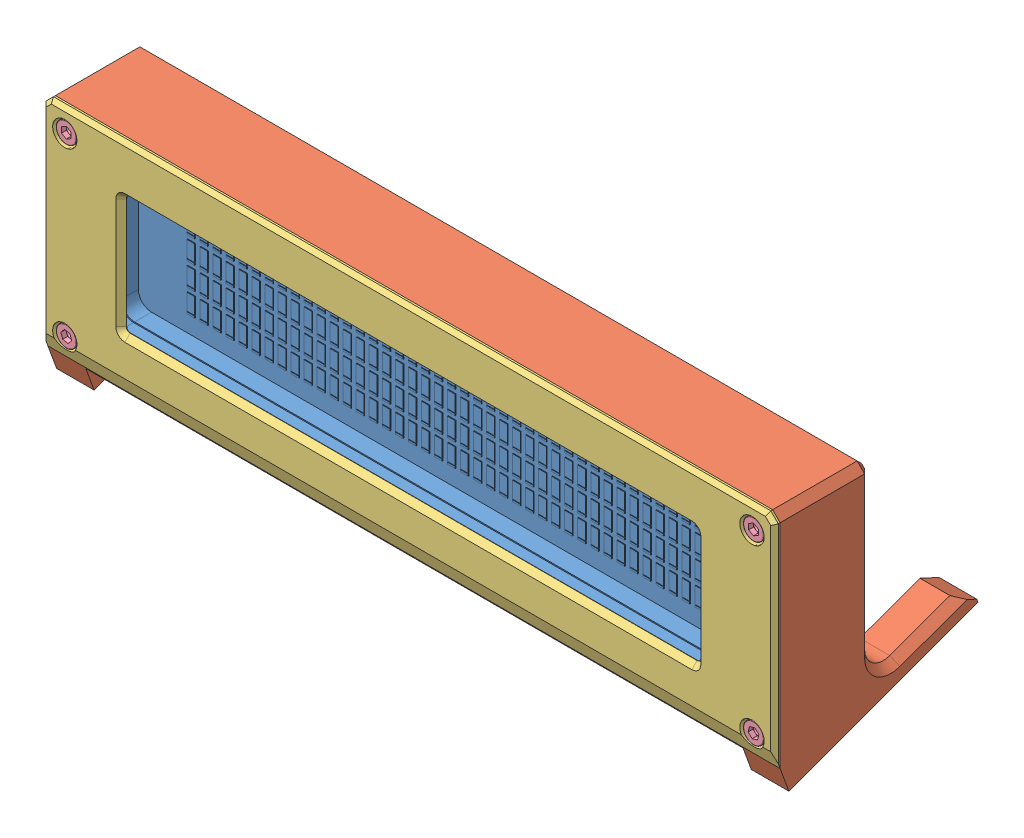
SolidWorks assembly Ensamblaje3, configuration Default. Lengths in mm.
Overall size (195 65.07 54.19).
244 component instances, 157 part files, 27 mates.
Components (placement in the parent):
- cu40045-uw1j-1: cu40045-uw1j [Default] at (-133.5972 17.1888 55.2046) size (190 54 18.77)
- 61301821121_Download_IGS_61301821121_rev1-1: 61301821121_Download_IGS_61301821121_rev1 [Default] at (-223.5572 15.9188 58.0746) x (0 -1 0) z (1 0 0) size (22.86 11.54 5.08)
  - DEFAULT-1: DEFAULT [Predeterminado] at origin size (22.86 11.54 5.08)
    - DEFAULT-1: DEFAULT [Predeterminado] at (-10.16 1.5 0) x (1 0 0) z (0 -1 0) size (0.64 0.64 11.54)
    - DEFAULT-2: DEFAULT [Predeterminado] at (-10.16 1.5 -2.54) x (1 0 0) z (0 -1 0) size (0.64 0.64 11.54)
    - DEFAULT-3: DEFAULT [Predeterminado] at (-7.62 1.5 0) x (1 0 0) z (0 -1 0) size (0.64 0.64 11.54)
    - DEFAULT-4: DEFAULT [Predeterminado] at (-7.62 1.5 -2.54) x (1 0 0) z (0 -1 0) size (0.64 0.64 11.54)
    - DEFAULT-5: DEFAULT [Predeterminado] at (-5.08 1.5 0) x (1 0 0) z (0 -1 0) size (0.64 0.64 11.54)
    - DEFAULT-6: DEFAULT [Predeterminado] at (-5.08 1.5 -2.54) x (1 0 0) z (0 -1 0) size (0.64 0.64 11.54)
    - DEFAULT-7: DEFAULT [Predeterminado] at (-2.54 1.5 0) x (1 0 0) z (0 -1 0) size (0.64 0.64 11.54)
    - DEFAULT-8: DEFAULT [Predeterminado] at (-2.54 1.5 -2.54) x (1 0 0) z (0 -1 0) size (0.64 0.64 11.54)
    - DEFAULT-9: DEFAULT [Predeterminado] at (0 1.5 0) x (1 0 0) z (0 -1 0) size (0.64 0.64 11.54)
    - DEFAULT-10: DEFAULT [Predeterminado] at (0 1.5 -2.54) x (1 0 0) z (0 -1 0) size (0.64 0.64 11.54)
    - DEFAULT-11: DEFAULT [Predeterminado] at (2.54 1.5 0) x (1 0 0) z (0 -1 0) size (0.64 0.64 11.54)
    - DEFAULT-12: DEFAULT [Predeterminado] at (2.54 1.5 -2.54) x (1 0 0) z (0 -1 0) size (0.64 0.64 11.54)
    - DEFAULT-13: DEFAULT [Predeterminado] at (5.08 1.5 0) x (1 0 0) z (0 -1 0) size (0.64 0.64 11.54)
    - DEFAULT-14: DEFAULT [Predeterminado] at (5.08 1.5 -2.54) x (1 0 0) z (0 -1 0) size (0.64 0.64 11.54)
    - DEFAULT-15: DEFAULT [Predeterminado] at (7.62 1.5 0) x (1 0 0) z (0 -1 0) size (0.64 0.64 11.54)
    - DEFAULT-16: DEFAULT [Predeterminado] at (7.62 1.5 -2.54) x (1 0 0) z (0 -1 0) size (0.64 0.64 11.54)
    - DEFAULT-17: DEFAULT [Predeterminado] at (10.16 1.5 0) x (1 0 0) z (0 -1 0) size (0.64 0.64 11.54)
    - DEFAULT-18: DEFAULT [Predeterminado] at (10.16 1.5 -2.54) x (1 0 0) z (0 -1 0) size (0.64 0.64 11.54)
    - DEFAULT-1-1: DEFAULT-1 [Predeterminado] at origin size (22.86 2.54 5.08)
- pic backpack-1: pic backpack [Default] at (-239.4322 -8.7192 50.6016) x (-1 0 0) z (0 0 -1) size (33.69 32.08 21.86)
  - Layer_1-1: Layer_1 [Predeterminado] at origin size (33.66 25.02 1.61)
  - J1-1: J1 [Predeterminado] at (-14.605 24.638 -0.803) x (0 -1 0) z (0 0 -1) size (22.86 7.4 5.5)
    - Open CASCADE STEP translator 6.8 1.2.1-1: Open CASCADE STEP translator 6.8 1.2.1 [Predeterminado] at origin size (22.86 7.4 5.5)
      - Body_1-1: Body_1 [Predeterminado] at origin size (22.86 7.4 5.5)
        - =_[0_1_1_2]-1: =_[0_1_1_2] [Predeterminado] at (0 0 0.1) size (22.86 5.08 3.7)
        - =_[0_1_1_3]-1: =_[0_1_1_3] [Predeterminado] at origin size (21.14 7.4 0.1)
          - SOLID-1: SOLID [Predeterminado] at origin size (0.82 1.58 0.1)
          - SOLID_2-1: SOLID_2 [Predeterminado] at origin size (0.82 1.58 0.1)
          - SOLID_3-1: SOLID_3 [Predeterminado] at origin size (0.82 1.58 0.1)
          - SOLID_4-1: SOLID_4 [Predeterminado] at origin size (0.82 1.58 0.1)
          - SOLID_5-1: SOLID_5 [Predeterminado] at origin size (0.82 1.58 0.1)
          - SOLID_6-1: SOLID_6 [Predeterminado] at origin size (0.82 1.58 0.1)
          - SOLID_7-1: SOLID_7 [Predeterminado] at origin size (0.82 1.58 0.1)
          - SOLID_8-1: SOLID_8 [Predeterminado] at origin size (0.82 1.58 0.1)
          - SOLID_9-1: SOLID_9 [Predeterminado] at origin size (0.82 1.58 0.1)
          - SOLID_10-1: SOLID_10 [Predeterminado] at origin size (0.82 1.58 0.1)
          - SOLID_11-1: SOLID_11 [Predeterminado] at origin size (0.82 1.58 0.1)
          - SOLID_12-1: SOLID_12 [Predeterminado] at origin size (0.82 1.58 0.1)
          - SOLID_13-1: SOLID_13 [Predeterminado] at origin size (0.82 1.58 0.1)
          - SOLID_14-1: SOLID_14 [Predeterminado] at origin size (0.82 1.58 0.1)
          - SOLID_15-1: SOLID_15 [Predeterminado] at origin size (0.82 1.58 0.1)
          - SOLID_16-1: SOLID_16 [Predeterminado] at origin size (0.82 1.58 0.1)
          - SOLID_17-1: SOLID_17 [Predeterminado] at origin size (0.82 1.58 0.1)
          - SOLID_18-1: SOLID_18 [Predeterminado] at origin size (0.82 1.58 0.1)
        - =_[0_1_1_4]-1: =_[0_1_1_4] [Predeterminado] at origin size (21.14 3.36 1.8)
          - SOLID_19-1: SOLID_19 [Predeterminado] at origin size (0.82 0.82 1.8)
          - SOLID_20-1: SOLID_20 [Predeterminado] at origin size (0.82 0.82 1.8)
          - SOLID_21-1: SOLID_21 [Predeterminado] at origin size (0.82 0.82 1.8)
          - SOLID_22-1: SOLID_22 [Predeterminado] at origin size (0.82 0.82 1.8)
          - SOLID_23-1: SOLID_23 [Predeterminado] at origin size (0.82 0.82 1.8)
          - SOLID_24-1: SOLID_24 [Predeterminado] at origin size (0.82 0.82 1.8)
          - SOLID_25-1: SOLID_25 [Predeterminado] at origin size (0.82 0.82 1.8)
          - SOLID_26-1: SOLID_26 [Predeterminado] at origin size (0.82 0.82 1.8)
          - SOLID_27-1: SOLID_27 [Predeterminado] at origin size (0.82 0.82 1.8)
          - SOLID_28-1: SOLID_28 [Predeterminado] at origin size (0.82 0.82 1.8)
          - SOLID_29-1: SOLID_29 [Predeterminado] at origin size (0.82 0.82 1.8)
          - SOLID_30-1: SOLID_30 [Predeterminado] at origin size (0.82 0.82 1.8)
          - SOLID_31-1: SOLID_31 [Predeterminado] at origin size (0.82 0.82 1.8)
          - SOLID_32-1: SOLID_32 [Predeterminado] at origin size (0.82 0.82 1.8)
          - SOLID_33-1: SOLID_33 [Predeterminado] at origin size (0.82 0.82 1.8)
          - SOLID_34-1: SOLID_34 [Predeterminado] at origin size (0.82 0.82 1.8)
          - SOLID_35-1: SOLID_35 [Predeterminado] at origin size (0.82 0.82 1.8)
          - SOLID_36-1: SOLID_36 [Predeterminado] at origin size (0.82 0.82 1.8)
          - SOLID_37-1: SOLID_37 [Predeterminado] at origin size (1.6 1.6 1.8)
          - SOLID_38-1: SOLID_38 [Predeterminado] at origin size (1.6 1.6 1.8)
  - U1-1: U1 [Predeterminado] at (-27.559 28.448 0.803) size (9.65 18 2.64)
    - Open CASCADE STEP translator 6.8 1.3.1-1: Open CASCADE STEP translator 6.8 1.3.1 [Predeterminado] at origin size (9.65 18 2.64)
      - Body_1-1: Body_1 [Predeterminado] at origin size (7.3 18 2.38)
      - Pin_1-1: Pin_1 [Predeterminado] at origin size (1.17 0.51 1.58)
      - Pin_2-1: Pin_2 [Predeterminado] at origin size (1.17 0.51 1.58)
      - Pin_3-1: Pin_3 [Predeterminado] at origin size (1.17 0.51 1.58)
      - Pin_4-1: Pin_4 [Predeterminado] at origin size (1.17 0.51 1.58)
      - Pin_5-1: Pin_5 [Predeterminado] at origin size (1.17 0.51 1.58)
      - Pin_6-1: Pin_6 [Predeterminado] at origin size (1.17 0.51 1.58)
      - Pin_7-1: Pin_7 [Predeterminado] at origin size (1.17 0.51 1.58)
      - Pin_8-1: Pin_8 [Predeterminado] at origin size (1.17 0.51 1.58)
      - Pin_9-1: Pin_9 [Predeterminado] at origin size (1.17 0.51 1.58)
      - Pin_10-1: Pin_10 [Predeterminado] at origin size (1.17 0.51 1.58)
      - Pin_11-1: Pin_11 [Predeterminado] at origin size (1.17 0.51 1.58)
      - Pin_12-1: Pin_12 [Predeterminado] at origin size (1.17 0.51 1.58)
      - Pin_13-1: Pin_13 [Predeterminado] at origin size (1.17 0.51 1.58)
      - Pin_14-1: Pin_14 [Predeterminado] at origin size (1.17 0.51 1.58)
      - Pin_15-1: Pin_15 [Predeterminado] at (18.8 -17.78 0) x (-1 0 0) z (0 0 1) size (1.17 0.51 1.58)
      - Pin_16-1: Pin_16 [Predeterminado] at (18.8 -15.24 0) x (-1 0 0) z (0 0 1) size (1.17 0.51 1.58)
      - Pin_17-1: Pin_17 [Predeterminado] at (18.8 -12.7 0) x (-1 0 0) z (0 0 1) size (1.17 0.51 1.58)
      - Pin_18-1: Pin_18 [Predeterminado] at (18.8 -10.16 0) x (-1 0 0) z (0 0 1) size (1.17 0.51 1.58)
      - Pin_19-1: Pin_19 [Predeterminado] at (18.8 -7.62 0) x (-1 0 0) z (0 0 1) size (1.17 0.51 1.58)
      - Pin_20-1: Pin_20 [Predeterminado] at (18.8 -5.08 0) x (-1 0 0) z (0 0 1) size (1.17 0.51 1.58)
      - Pin_21-1: Pin_21 [Predeterminado] at (18.8 -2.54 0) x (-1 0 0) z (0 0 1) size (1.17 0.51 1.58)
      - Pin_22-1: Pin_22 [Predeterminado] at (18.8 0 0) x (-1 0 0) z (0 0 1) size (1.17 0.51 1.58)
      - Pin_23-1: Pin_23 [Predeterminado] at (18.8 2.54 0) x (-1 0 0) z (0 0 1) size (1.17 0.51 1.58)
      - Pin_24-1: Pin_24 [Predeterminado] at (18.8 5.08 0) x (-1 0 0) z (0 0 1) size (1.17 0.51 1.58)
      - Pin_25-1: Pin_25 [Predeterminado] at (18.8 7.62 0) x (-1 0 0) z (0 0 1) size (1.17 0.51 1.58)
      - Pin_26-1: Pin_26 [Predeterminado] at (18.8 10.16 0) x (-1 0 0) z (0 0 1) size (1.17 0.51 1.58)
      - Pin_27-1: Pin_27 [Predeterminado] at (18.8 12.7 0) x (-1 0 0) z (0 0 1) size (1.17 0.51 1.58)
      - Pin_28-1: Pin_28 [Predeterminado] at (18.8 15.24 0) x (-1 0 0) z (0 0 1) size (1.17 0.51 1.58)
  - U2-1: U2 [Predeterminado] at (-20.066 16.383 0.803) x (-1 0 0) z (0 0 1) size (5 3.22 1.3)
    - Open CASCADE STEP translator 6.8 1.4.1-1: Open CASCADE STEP translator 6.8 1.4.1 [Predeterminado] at origin size (5 3.22 1.3)
      - Body_1_2-1: Body_1_2 [Predeterminado] at (0 0 0.25) x (1 0 0) z (0 -1 0) size (5 1.3 3.22)
        - =_[0_1_1_3]-1: =_[0_1_1_3] [Predeterminado] at origin size (1.25 0.05 2)
        - =_[0_1_1_4]-1: =_[0_1_1_4] [Predeterminado] at origin size (1.25 0.05 2)
        - =_[0_1_1_5]-1: =_[0_1_1_5] [Predeterminado] at origin size (5 1.3 3.22)
  - C2-1: C2 [Predeterminado] at (-26.035 17.907 0.803) x (0 -1 0) z (0 0 1) size (2.34 1.04 0.5)
    - Open CASCADE STEP translator 6.8 1.5.1-1: Open CASCADE STEP translator 6.8 1.5.1 [Predeterminado] at origin size (2.34 1.04 0.5)
      - Body_1_2-1: Body_1_2 [Predeterminado] at origin size (2.29 1.04 0.43)
      - Pin_1_2-1: Pin_1_2 [Predeterminado] at (0.3048 0 0) x (-1 0 0) z (0 0 1) size (0.51 1.02 0.5)
      - Pin_2_2-1: Pin_2_2 [Predeterminado] at origin size (0.51 1.02 0.5)
  - C4-1: C4 [Predeterminado] at (-29.591 16.383 0.803) x (0 1 0) z (0 0 1) size (2.34 1.04 0.5)
    - Open CASCADE STEP translator 6.8 1.5.1-1: Open CASCADE STEP translator 6.8 1.5.1 [Predeterminado] at origin size (2.34 1.04 0.5)
      - Body_1_2-1: Body_1_2 [Predeterminado] at origin size (2.29 1.04 0.43)
      - Pin_1_2-1: Pin_1_2 [Predeterminado] at (0.3048 0 0) x (-1 0 0) z (0 0 1) size (0.51 1.02 0.5)
      - Pin_2_2-1: Pin_2_2 [Predeterminado] at origin size (0.51 1.02 0.5)
  - C5-1: C5 [Predeterminado] at (-21.971 13.716 0.803) size (2.34 1.04 0.5)
    - Open CASCADE STEP translator 6.8 1.5.1-1: Open CASCADE STEP translator 6.8 1.5.1 [Predeterminado] at origin size (2.34 1.04 0.5)
      - Body_1_2-1: Body_1_2 [Predeterminado] at origin size (2.29 1.04 0.43)
      - Pin_1_2-1: Pin_1_2 [Predeterminado] at (0.3048 0 0) x (-1 0 0) z (0 0 1) size (0.51 1.02 0.5)
      - Pin_2_2-1: Pin_2_2 [Predeterminado] at origin size (0.51 1.02 0.5)
  - C1-1: C1 [Predeterminado] at (-24.257 17.8816 0.803) x (0 -1 0) z (0 0 1) size (2.34 1.04 0.5)
    - Open CASCADE STEP translator 6.8 1.5.1-1: Open CASCADE STEP translator 6.8 1.5.1 [Predeterminado] at origin size (2.34 1.04 0.5)
      - Body_1_2-1: Body_1_2 [Predeterminado] at origin size (2.29 1.04 0.43)
      - Pin_1_2-1: Pin_1_2 [Predeterminado] at (0.3048 0 0) x (-1 0 0) z (0 0 1) size (0.51 1.02 0.5)
      - Pin_2_2-1: Pin_2_2 [Predeterminado] at origin size (0.51 1.02 0.5)
  - C3-1: C3 [Predeterminado] at (-27.813 16.383 0.803) x (0 1 0) z (0 0 1) size (2.34 1.04 0.5)
    - Open CASCADE STEP translator 6.8 1.5.1-1: Open CASCADE STEP translator 6.8 1.5.1 [Predeterminado] at origin size (2.34 1.04 0.5)
      - Body_1_2-1: Body_1_2 [Predeterminado] at origin size (2.29 1.04 0.43)
      - Pin_1_2-1: Pin_1_2 [Predeterminado] at (0.3048 0 0) x (-1 0 0) z (0 0 1) size (0.51 1.02 0.5)
      - Pin_2_2-1: Pin_2_2 [Predeterminado] at origin size (0.51 1.02 0.5)
  - JP1-1: JP1 [Predeterminado] at (-29.845 21.082 0.803) x (0 1 0) z (0 0 1) size (2 1.5 0.63)
    - Open CASCADE STEP translator 6.8 1.11.1-1: Open CASCADE STEP translator 6.8 1.11.1 [Predeterminado] at origin size (2 1.5 0.63)
      - Body_1_4-1: Body_1_4 [Predeterminado] at origin size (2 1 0.03)
      - Pin_1_3-1: Pin_1_3 [Predeterminado] x (0 1 0) z (0 0 1) size (1.5 0.59 0.63)
      - Pin_2_3-1: Pin_2_3 [Predeterminado] at (1 -1 0) x (0 1 0) z (0 0 1) size (1.5 0.59 0.63)
  - Q1-1: Q1 [Predeterminado] at (-30.8 28.559 0.803) x (0 1 0) z (0 0 1) size (2.4 2.9 1.2)
    - Open CASCADE STEP translator 6.8 1.12.1-1: Open CASCADE STEP translator 6.8 1.12.1 [Predeterminado] at origin size (2.4 2.9 1.2)
      - Body_1_3-1: Body_1_3 [Predeterminado] at origin size (2.4 2.9 1.2)
        - =_[0_1_1_2]_2-1: =_[0_1_1_2]_2 [Predeterminado] at origin size (1.3 2.9 1.15)
        - =_[0_1_1_3]_2-1: =_[0_1_1_3]_2 [Predeterminado] at origin size (0.55 2.3 0.61)
          - SOLID_39-1: SOLID_39 [Predeterminado] at origin size (0.55 0.4 0.61)
          - SOLID_40-1: SOLID_40 [Predeterminado] at origin size (0.55 0.4 0.61)
        - =_[0_1_1_4]_2-1: =_[0_1_1_4]_2 [Predeterminado] at origin size (0.55 0.4 0.61)
  - R1-1: R1 [Predeterminado] at (-29.845 36.0426 0.803) x (0 -1 0) z (0 0 1) size (2.34 1.04 0.5)
    - Open CASCADE STEP translator 6.8 1.13.1-1: Open CASCADE STEP translator 6.8 1.13.1 [Predeterminado] at origin size (2.34 1.04 0.5)
      - Body_1_5-1: Body_1_5 [Predeterminado] at origin size (2.29 1.04 0.43)
      - Pin_1_4-1: Pin_1_4 [Predeterminado] at (0.3048 0 0) x (-1 0 0) z (0 0 1) size (0.51 1.02 0.5)
      - Pin_2_4-1: Pin_2_4 [Predeterminado] at origin size (0.51 1.02 0.5)
  - R2-1: R2 [Predeterminado] at (-31.623 36.068 0.803) x (0 -1 0) z (0 0 1) size (2.34 1.04 0.5)
    - Open CASCADE STEP translator 6.8 1.13.1-1: Open CASCADE STEP translator 6.8 1.13.1 [Predeterminado] at origin size (2.34 1.04 0.5)
      - Body_1_5-1: Body_1_5 [Predeterminado] at origin size (2.29 1.04 0.43)
      - Pin_1_4-1: Pin_1_4 [Predeterminado] at (0.3048 0 0) x (-1 0 0) z (0 0 1) size (0.51 1.02 0.5)
      - Pin_2_4-1: Pin_2_4 [Predeterminado] at origin size (0.51 1.02 0.5)
  - J4-1: J4 [Predeterminado] at (-39.3381 34.5271 0.803) x (0 -1 0) z (0 0 1) size (30.95 12.2 21.86)
    - Open CASCADE STEP translator 6.8 1.15.1-1: Open CASCADE STEP translator 6.8 1.15.1 [Predeterminado] at origin size (30.95 12.2 21.86)
      - Body_1_4-1: Body_1_4 [Predeterminado] at (2.8 -2.8 0.11) x (1 0 0) z (0 -1 0) size (30.95 21.86 12.2)
        - Imported-1: Imported [Predeterminado] at (22 -7.19 8.4402) x (-1 0 0) z (0 0.000001 1) size (8.94 8.16 3.49)
        - Imported-2: Imported [Predeterminado] at (72.395 48.5033 -3.3613) x (1 0 0) z (0 1 -0.000001) size (8.94 3.77 7.85)
          - SHELL-1: SHELL [Predeterminado] at origin size (0.19 0.16 0.35)
          - SHELL_2-1: SHELL_2 [Predeterminado] at origin size (0.26 0.3 0.35)
          - SHELL_3-1: SHELL_3 [Predeterminado] at origin size (0.26 0.31 0.35)
          - SHELL_4-1: SHELL_4 [Predeterminado] at origin size (0.3 0.16 0.3)
          - SHELL_5-1: SHELL_5 [Predeterminado] at origin size (0.3 0.16 0.3)
          - SHELL_6-1: SHELL_6 [Predeterminado] at origin size (0.48 0.17 0.48)
          - SHELL_7-1: SHELL_7 [Predeterminado] at origin size (0.48 0.17 0.48)
          - SHELL_8-1: SHELL_8 [Predeterminado] at origin size (0.16 0.5 0.5)
          - SHELL_9-1: SHELL_9 [Predeterminado] at origin size (0.16 0.5 0.5)
          - SHELL_10-1: SHELL_10 [Predeterminado] at origin size (0.19 0.16 0.35)
          - ASSEMBLY-1: ASSEMBLY [Predeterminado] at origin size (8.94 3.77 7.85)
            - SHELL_11-1: SHELL_11 [Predeterminado] at origin size (8.94 3.77 7.85)
            - SHELL_12-1: SHELL_12 [Predeterminado] at origin size (0.2 0.01 0)
            - SHELL_13-1: SHELL_13 [Predeterminado] at origin size (0.2 0.01 0)
            - SHELL_14-1: SHELL_14 [Predeterminado] at origin size (0.2 0.01 0)
          - SHELL_16-1: SHELL_16 [Predeterminado] at origin size (0.21 0.01 0.02)
          - SHELL_17-1: SHELL_17 [Predeterminado] at origin size (0.2 0 0.01)
          - SHELL_18-1: SHELL_18 [Predeterminado] at origin size (0.2 0.1 0.1)
          - SHELL_19-1: SHELL_19 [Predeterminado] at origin size (0.2 0.1 0.1)
          - SHELL_20-1: SHELL_20 [Predeterminado] at origin size (0.2 0.1 0.1)
          - SHELL_21-1: SHELL_21 [Predeterminado] at origin size (0.2 0.1 0.1)
  - J5-1: J5 [Predeterminado] at (-36.576 24.384 0.803) x (0 -1 0) z (0 0 1) size (8.94 7.71 4.41) (hidden)
    - Open CASCADE STEP translator 6.8 1.16.1-1: Open CASCADE STEP translator 6.8 1.16.1 [Predeterminado] at origin size (8.94 7.71 4.41)
      - Body_1_5-1: Body_1_5 [Predeterminado] at (3.2 -4.8 0) x (1 0 0) z (0 -1 0) size (8.94 4.41 7.71)
        - Imported_2-1: Imported_2 [Predeterminado] at (0 0 -1.255) size (8.94 4.41 7.71)
          - SOLID_41-1: SOLID_41 [Predeterminado] at origin size (0.25 0.05 2.38)
          - SOLID_42-1: SOLID_42 [Predeterminado] at origin size (0.25 0.05 2.38)
          - SOLID_43-1: SOLID_43 [Predeterminado] at origin size (0.25 0.05 1.88)
          - SOLID_44-1: SOLID_44 [Predeterminado] at origin size (0.25 0.05 1.88)
          - SOLID_45-1: SOLID_45 [Predeterminado] at origin size (0.25 0.05 1.88)
          - SOLID_46-1: SOLID_46 [Predeterminado] at origin size (0.25 0.05 1.88)
          - SOLID_47-1: SOLID_47 [Predeterminado] at origin size (0.25 0.05 1.88)
          - SOLID_48-1: SOLID_48 [Predeterminado] at origin size (0.25 0.05 1.88)
          - SOLID_49-1: SOLID_49 [Predeterminado] at origin size (0.25 0.05 1.88)
          - SOLID_50-1: SOLID_50 [Predeterminado] at origin size (0.25 0.05 1.88)
          - SOLID_51-1: SOLID_51 [Predeterminado] at origin size (0.25 0.05 2.38)
          - SOLID_52-1: SOLID_52 [Predeterminado] at origin size (0.25 0.05 2.38)
          - SOLID_53-1: SOLID_53 [Predeterminado] at origin size (0.25 0.05 2.38)
          - SOLID_54-1: SOLID_54 [Predeterminado] at origin size (0.25 0.05 1.88)
          - SOLID_55-1: SOLID_55 [Predeterminado] at origin size (0.25 0.05 1.88)
          - SOLID_56-1: SOLID_56 [Predeterminado] at origin size (0.25 0.05 2.38)
          - SOLID_57-1: SOLID_57 [Predeterminado] at origin size (0.25 0.05 1.88)
          - SOLID_58-1: SOLID_58 [Predeterminado] at origin size (0.25 0.05 1.88)
          - SOLID_59-1: SOLID_59 [Predeterminado] at origin size (0.25 0.05 1.88)
          - SOLID_60-1: SOLID_60 [Predeterminado] at origin size (0.25 0.05 1.88)
          - SOLID_61-1: SOLID_61 [Predeterminado] at origin size (0.25 0.05 2.38)
          - SOLID_62-1: SOLID_62 [Predeterminado] at origin size (0.25 0.05 1.88)
          - SOLID_63-1: SOLID_63 [Predeterminado] at origin size (0.25 0.05 1.88)
          - SOLID_64-1: SOLID_64 [Predeterminado] at origin size (0.25 0.05 2.38)
          - SOLID_65-1: SOLID_65 [Predeterminado] at origin size (0.35 0.1 1.82)
          - SOLID_66-1: SOLID_66 [Predeterminado] at origin size (0.35 0.1 1.82)
          - SOLID_67-1: SOLID_67 [Predeterminado] at origin size (0.2 0.32 0.73)
          - SOLID_68-1: SOLID_68 [Predeterminado] at origin size (0.2 0.32 0.73)
          - SOLID_69-1: SOLID_69 [Predeterminado] at origin size (0.2 0.32 0.73)
          - SOLID_70-1: SOLID_70 [Predeterminado] at origin size (0.2 0.32 0.73)
          - SOLID_71-1: SOLID_71 [Predeterminado] at origin size (0.2 0.32 0.73)
          - SOLID_72-1: SOLID_72 [Predeterminado] at origin size (0.2 0.32 0.73)
          - SOLID_73-1: SOLID_73 [Predeterminado] at origin size (0.2 0.32 0.73)
          - SOLID_74-1: SOLID_74 [Predeterminado] at origin size (0.2 0.32 0.73)
          - SOLID_75-1: SOLID_75 [Predeterminado] at origin size (0.2 0.32 0.73)
          - SOLID_76-1: SOLID_76 [Predeterminado] at origin size (0.2 0.32 0.73)
          - SOLID_77-1: SOLID_77 [Predeterminado] at origin size (0.2 0.32 0.73)
          - SOLID_78-1: SOLID_78 [Predeterminado] at origin size (0.2 0.32 0.73)
          - SOLID_79-1: SOLID_79 [Predeterminado] at origin size (0.2 0.32 0.73)
          - SOLID_80-1: SOLID_80 [Predeterminado] at origin size (0.2 0.32 0.73)
          - SOLID_81-1: SOLID_81 [Predeterminado] at origin size (0.2 0.32 0.73)
          - SOLID_82-1: SOLID_82 [Predeterminado] at origin size (0.2 0.32 0.73)
          - SOLID_83-1: SOLID_83 [Predeterminado] at origin size (8.94 4.41 7.34)
          - SOLID_84-1: SOLID_84 [Predeterminado] at origin size (8.89 3.61 6.57)
  - R3-1: R3 [Predeterminado] at (-33.909 20.574 0.803) x (0 1 0) z (0 0 1) size (2.34 1.04 0.5)
    - Open CASCADE STEP translator 6.8 1.13.1-1: Open CASCADE STEP translator 6.8 1.13.1 [Predeterminado] at origin size (2.34 1.04 0.5)
      - Body_1_5-1: Body_1_5 [Predeterminado] at origin size (2.29 1.04 0.43)
      - Pin_1_4-1: Pin_1_4 [Predeterminado] at (0.3048 0 0) x (-1 0 0) z (0 0 1) size (0.51 1.02 0.5)
      - Pin_2_4-1: Pin_2_4 [Predeterminado] at origin size (0.51 1.02 0.5)
  - R4-1: R4 [Predeterminado] at (-32.004 20.574 0.803) x (0 1 0) z (0 0 1) size (2.34 1.04 0.5)
    - Open CASCADE STEP translator 6.8 1.13.1-1: Open CASCADE STEP translator 6.8 1.13.1 [Predeterminado] at origin size (2.34 1.04 0.5)
      - Body_1_5-1: Body_1_5 [Predeterminado] at origin size (2.29 1.04 0.43)
      - Pin_1_4-1: Pin_1_4 [Predeterminado] at (0.3048 0 0) x (-1 0 0) z (0 0 1) size (0.51 1.02 0.5)
      - Pin_2_4-1: Pin_2_4 [Predeterminado] at origin size (0.51 1.02 0.5)
- Pieza6-1: Pieza6 [Default] at (-133.5972 17.1888 55.2046) x (-1 0 0) z (0 0 -1) size (195 65.07 52.69)
- Pieza7-1: Pieza7 [Default] at (-133.5972 17.1888 68.2046) size (195 58.7 10.5)
- socket head cap screw_iso-1: socket head cap screw_iso [ISO 4762 M3 x 16 - 16N] at (-225.0972 -6.3112 69.3046) x (0 0 -1) z (0.939693 0.34202 0) size (19 5.5 5.5)
- socket head cap screw_iso-2: socket head cap screw_iso [ISO 4762 M3 x 16 - 16N] at (-225.0972 40.6888 69.3046) x (0 0 -1) z (1 0 0) size (19 5.5 5.5)
- socket head cap screw_iso-3: socket head cap screw_iso [ISO 4762 M3 x 16 - 16N] at (-42.0972 40.6888 69.3046) x (0 0 -1) z (1 0 0) size (19 5.5 5.5)
- socket head cap screw_iso-4: socket head cap screw_iso [ISO 4762 M3 x 16 - 16N] at (-42.0972 -6.3112 69.3046) x (0 0 -1) z (-0.970596 0.240715 0) size (19 5.5 5.5)
- NHD-0440WH-ATFH-JT#-1: NHD-0440WH-ATFH-JT# [Default] at (-133.5972 17.1888 57.6046) size (190 54 12.7) (hidden)
Mates (geometry in assembly coordinates):
- Coincidente1: coincident anti-aligned: plane of cu40045-uw1j-1 through (-232.3972 -10.8912 55.2046) normal (0 0 -1); plane of 61301821121_Download_IGS_61301821121_rev1-1/DEFAULT-1/DEFAULT-1-1 through (-227.0272 27.2831 55.2046) normal (0 0 1)
- Concéntrica1: concentric: cylinder of cu40045-uw1j-1 through (-226.0972 26.0788 56.8046) axis (0 0 -1) radius 0.5; point of 61301821121_Download_IGS_61301821121_rev1-1/DEFAULT-1/DEFAULT-2
- Paralelo1: parallel aligned: plane of cu40045-uw1j-1 through (-228.5972 45.2688 54.9665) normal (-1 0 0); plane of 61301821121_Download_IGS_61301821121_rev1-1/DEFAULT-1/DEFAULT-1-1 through (-227.3672 22.5188 56.8046) normal (-1 0 0)
- Coincidente4: coincident aligned: plane of 61301821121_Download_IGS_61301821121_rev1-1/DEFAULT-1/DEFAULT-1-1 through (-227.3672 25.0588 56.8046) normal (-1 0 0); plane of pic backpack-1/J1-1/Open CASCADE STEP translator 6.8 1.2.1-1/Body_1-1/=_[0_1_1_2]-1 through (-227.3672 4.4888 51.5046) normal (-1 0 0)
- Paralelo2: parallel anti-aligned: plane of cu40045-uw1j-1 through (-232.3972 -10.8912 55.2046) normal (0 0 -1); plane of pic backpack-1/Layer_1-1 through (-229.1452 28.6188 51.4046) normal (0 0 1)
- Coincidente6: coincident aligned: plane of 61301821121_Download_IGS_61301821121_rev1-1/DEFAULT-1/DEFAULT-1-1 through (-226.8672 27.3488 58.9067) normal (0 1 0); plane of pic backpack-1/J1-1/Open CASCADE STEP translator 6.8 1.2.1-1/Body_1-1/=_[0_1_1_2]-1 through (-227.3672 27.3488 51.5046) normal (0 1 0)
- Coincidente7: coincident anti-aligned: plane of cu40045-uw1j-1 through (-232.3972 -10.8912 55.2046) normal (0 0 -1); plane of pic backpack-1/J1-1/Open CASCADE STEP translator 6.8 1.2.1-1/Body_1-1/=_[0_1_1_2]-1 through (-224.8272 15.9188 55.2046) normal (0 0 1)
- Coincidente8: coincident anti-aligned: plane of cu40045-uw1j-1 through (-232.3972 -10.8912 56.8046) normal (0 0 1); plane of 61301821121_Download_IGS_61301821121_rev1-1/DEFAULT-1/DEFAULT-1-1 through (-227.3672 27.3488 56.8046) normal (0 0 -1)
- EnPosición1: in place: plane of cu40045-uw1j-1 through (-232.3972 -10.8912 55.2046) normal (0 0 -1); plane of ? through (0 0 55.2046) normal (0 0 -1); moOrthogonalPlaneRef_w of cu40045-uw1j-1 through (-232.3972 -10.8912 55.2046) normal (0 0 -1); plane of ? through (0 0 55.2046) normal (0 1 0); plane of cu40045-uw1j-1 through (-232.3972 -10.8912 55.2046) normal (0 0 -1); plane of ? through (0 0 55.2046) normal (-1 0 0); plane of cu40045-uw1j-1 through (-232.3972 -10.8912 55.2046) normal (0 0 -1); unknown of Pieza6-1
- Coincidente9: coincident aligned: plane of cu40045-uw1j-1; plane of Pieza6-1
- Coincidente10: coincident aligned: moOrthogonalPlaneRef_w of cu40045-uw1j-1 through (-133.5972 17.1888 55.2046) normal (0 1 0); plane of Pieza6-1 through (-133.5972 17.1888 55.2046) normal (0 1 0)
- Coincidente11: coincident anti-aligned: moOrthogonalPlaneRef_w of cu40045-uw1j-1 through (-133.5972 17.1888 55.2046) normal (1 0 0); plane of Pieza6-1 through (-133.5972 17.1888 55.2046) normal (-1 0 0)
- EnPosición2: in place: plane of Pieza6-1 through (-221.9972 -2.8512 68.2046) normal (0 0 1); plane of ? through (0 0 68.2046) normal (0 0 1); plane of Pieza6-1 through (-221.9972 -2.8512 68.2046) normal (0 0 1); plane of ? through (0 0 68.2046) normal (0 1 0); plane of Pieza6-1 through (-221.9972 -2.8512 68.2046) normal (0 0 1); plane of ? through (0 0 68.2046) normal (1 0 0); plane of Pieza6-1 through (-221.9972 -2.8512 68.2046) normal (0 0 1); unknown of Pieza7-1
- Coincidente12: coincident aligned: plane of Pieza6-1; plane of Pieza7-1
- Coincidente13: coincident aligned: moOrthogonalPlaneRef_w of Pieza6-1 through (-133.5972 17.1888 68.2046) normal (0 1 0); plane of Pieza7-1 through (-133.5972 17.1888 68.2046) normal (0 1 0)
- Coincidente14: coincident anti-aligned: moOrthogonalPlaneRef_w of Pieza6-1 through (-133.5972 17.1888 68.2046) normal (-1 0 0); plane of Pieza7-1 through (-133.5972 17.1888 68.2046) normal (1 0 0)
- Concéntrica2: concentric aligned: cylinder of Pieza7-1 through (-225.0972 -6.3112 69.7046) axis (0 0 1) radius 1.7; cylinder of socket head cap screw_iso-1 through (-225.0972 -6.3112 101.0546) axis (0 0 1) radius 2.75
- Coincidente15: coincident anti-aligned: plane of Pieza7-1 through (-223.3972 -6.3112 66.3046) normal (0 0 1); plane of socket head cap screw_iso-1 through (-226.0377 -3.7271 66.3046) normal (0 0 -1)
- Concéntrica3: concentric aligned: cylinder of Pieza7-1 through (-225.0972 40.6888 69.7046) axis (0 0 1) radius 1.7; cylinder of socket head cap screw_iso-2 through (-225.0972 40.6888 101.0546) axis (0 0 1) radius 2.75
- Coincidente16: coincident anti-aligned: plane of Pieza7-1 through (-223.3972 40.6888 66.3046) normal (0 0 1); plane of socket head cap screw_iso-2 through (-225.0972 43.4388 66.3046) normal (0 0 -1)
- Concéntrica4: concentric aligned: cylinder of Pieza7-1 through (-42.0972 40.6888 69.7046) axis (0 0 1) radius 1.7; cylinder of socket head cap screw_iso-3 through (-42.0972 40.6888 101.0546) axis (0 0 1) radius 2.75
- Coincidente17: coincident anti-aligned: plane of Pieza7-1 through (-40.3972 40.6888 66.3046) normal (0 0 1); plane of socket head cap screw_iso-3 through (-42.0972 43.4388 66.3046) normal (0 0 -1)
- Concéntrica5: concentric aligned: cylinder of Pieza7-1 through (-42.0972 -6.3112 69.7046) axis (0 0 1) radius 1.7; cylinder of socket head cap screw_iso-4 through (-42.0972 -6.3112 101.0546) axis (0 0 1) radius 2.75
- Coincidente18: coincident anti-aligned: plane of Pieza7-1 through (-40.3972 -6.3112 66.3046) normal (0 0 1); plane of socket head cap screw_iso-4 through (-42.7591 -8.9804 66.3046) normal (0 0 -1)
- Coincidente19: coincident anti-aligned: plane of Pieza7-1 through (-133.5972 17.1888 68.2046) normal (0 0 -1); plane of NHD-0440WH-ATFH-JT#-1 through (-133.5972 17.1888 68.2046) normal (0 0 1)
- Coincidente20: coincident aligned: plane of Pieza7-1 through (-133.5972 17.1888 68.2046) normal (1 0 0); plane of NHD-0440WH-ATFH-JT#-1 through (-133.5972 17.1888 57.6046) normal (1 0 0)
- Coincidente21: coincident aligned: plane of Pieza7-1 through (-133.5972 17.1888 68.2046) normal (0 1 0); plane of NHD-0440WH-ATFH-JT#-1 through (-133.5972 17.1888 57.6046) normal (0 1 0)
